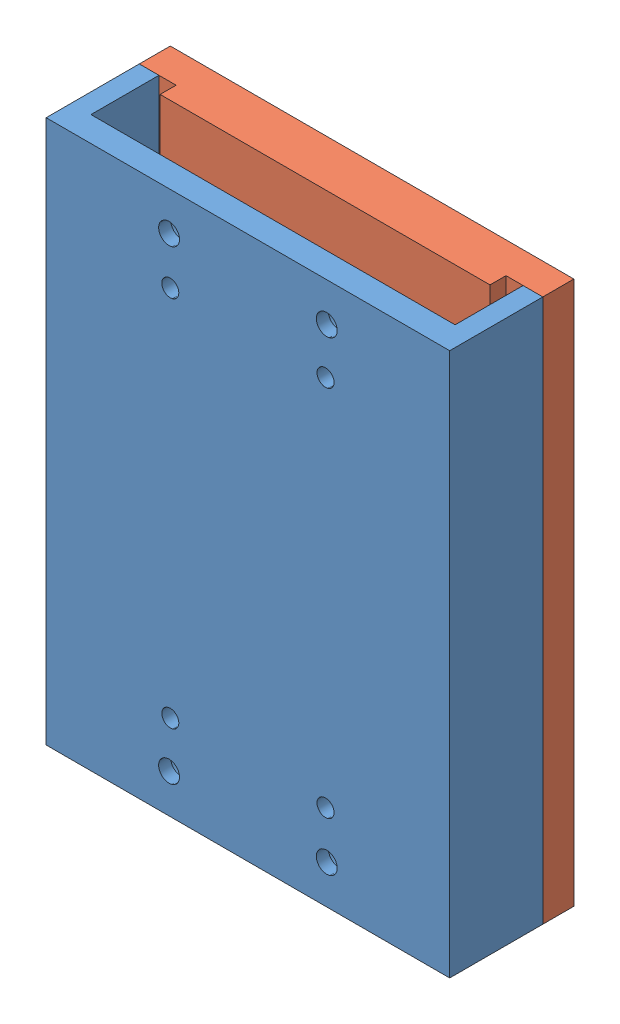
SolidWorks assembly Stage, configuration Default. Lengths in mm.
Overall size (130 175 40).
2 component instances, 2 part files, 3 mates.
Components (placement in the parent):
- Stage base-1: Stage base [Default] at (80.7259 98.455 136.3552) size (130 175 30)
- Stage top-1: Stage top [Default] at (80.7259 98.455 96.3552) x (1 0 0) z (0 1 0) size (130 15.15 175)
Mates (geometry in assembly coordinates):
- Coincident1: coincident: plane of Stage base-1 through (139.3759 185.955 106.3552) normal (0 0 -1); plane of Stage top-1 through (133.8589 141.2067 106.3552) normal (0 0 1)
- Coincident2: coincident: plane of Stage base-1 through (145.7259 185.955 136.3552) normal (1 0 0); plane of Stage top-1 through (145.7259 141.2067 96.3552) normal (1 0 0)
- Coincident3: coincident aligned: plane of Stage base-1 through (80.7259 185.955 136.3552) normal (0 1 0); plane of Stage top-1 through (80.7259 185.955 96.3552) normal (0 1 0)
